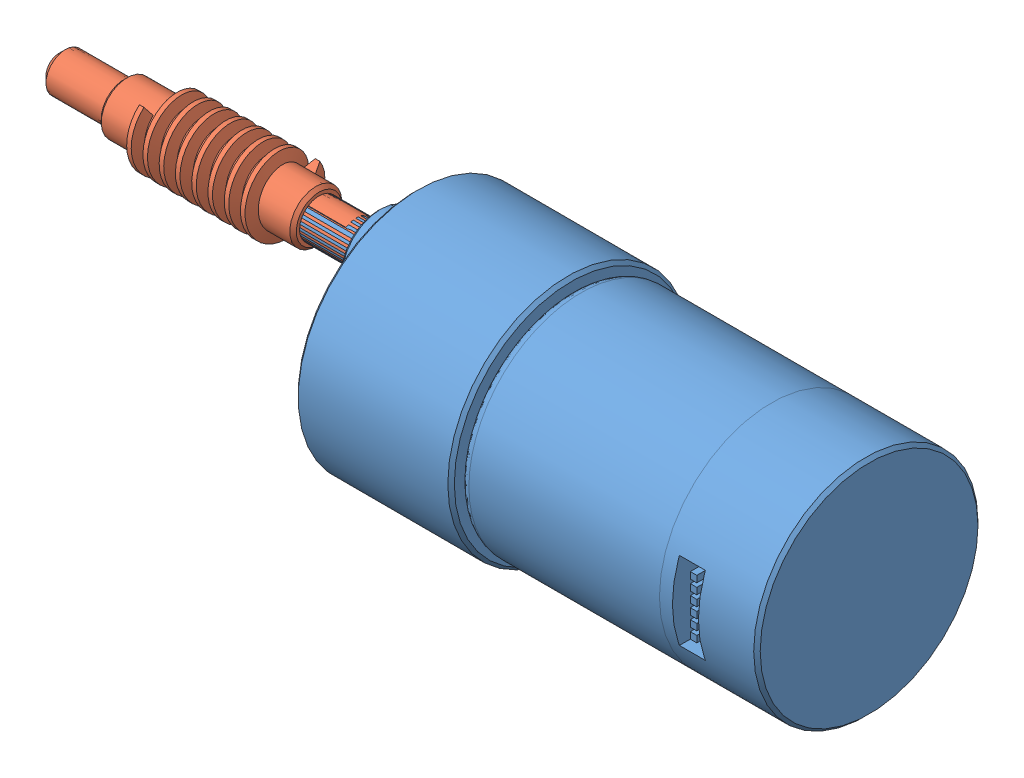
SolidWorks assembly Assem2, configuration Default. Lengths in mm.
Overall size (124.6 37 37).
2 component instances, 2 part files, 2 mates.
Components (placement in the parent):
- DC 12v 251rpm-1: DC 12v 251rpm [Default] at (7.6107 40.2325 75.549) size (90.8 37 37)
- 螺杆-1: 螺杆 [默认] at (-32.1893 47.2325 75.549) x (0 0.817077 0.576529) z (1 0 0) size (11 11.57 50)
Mates (geometry in assembly coordinates):
- Concentric1: concentric: circle of DC 12v 251rpm-1; circle of 螺杆-1
- Coincident1: coincident: circle of DC 12v 251rpm-1; circle of 螺杆-1
